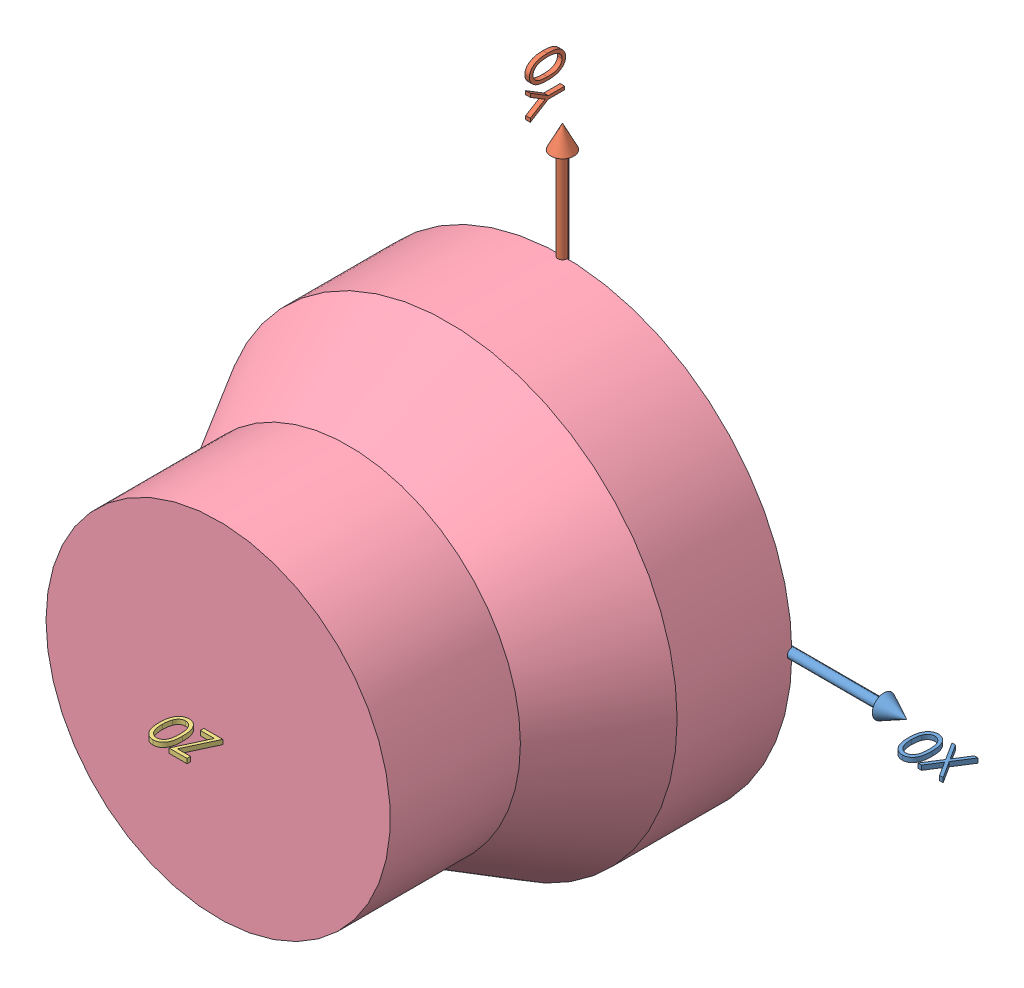
SolidWorks assembly base_link, configuration Default. Lengths in mm.
Overall size (281.06 280.58 177.88).
5 component instances, 4 part files, 6 mates.
Components (placement in the parent):
- frame0_xyz-1: frame0_xyz [Default] at origin size (191.71 185.58 177.88)
  - frame_arrowX0-1: frame_arrowX0 [Default] x (0 0 -1) z (1 0 0) size (20.38 10 181.06)
  - frame_arrowY0-2: frame_arrowY0 [Default] x (0 0 1) z (0 1 0) size (20.38 10 180.58)
  - frame_arrowZ0-3: frame_arrowZ0 [Default] x (0 -1 0) z (0 0 1) size (10 20.19 172.88)
- link0-1: link0 [Default] at origin size (200 200 150)
Mates (geometry in assembly coordinates):
- Coincident4: coincident aligned: plane of frame0_xyz-1 through (0 0 0) normal (0 0 1); plane of link0-1 through (0 0 0) normal (0 0 1)
- Coincident5: coincident aligned: plane of frame0_xyz-1 through (0 0 0) normal (0 1 0); plane of link0-1 through (0 0 0) normal (0 1 0)
- Coincident6: coincident aligned: plane of frame0_xyz-1 through (0 0 0) normal (1 0 0); plane of link0-1 through (0 0 0) normal (1 0 0)
- Coincident7: coincident aligned: plane of frame0_xyz-1 through (0 0 0) normal (0 0 1)
- Coincident8: coincident aligned: plane of frame0_xyz-1 through (0 0 0) normal (0 1 0)
- Coincident9: coincident aligned: plane of frame0_xyz-1 through (0 0 0) normal (1 0 0)
